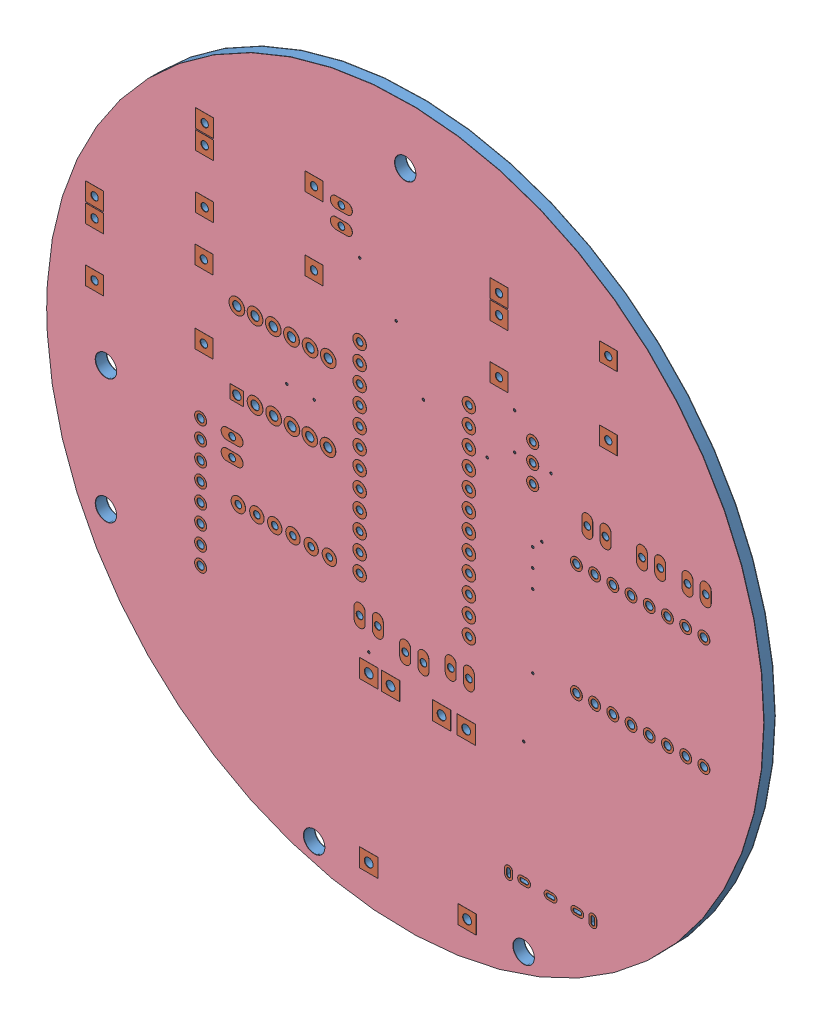
SolidWorks assembly RolyPoly PCB v1 SLDWRKS, configuration Default. Lengths in mm.
Overall size (100 100 1.64).
6 component instances, 5 part files, 0 mates.
Components (placement in the parent):
- RolyPoly PCB v1.step-1: RolyPoly PCB v1.step [Default] at origin size (100 100 1.64)
  - Board.step-1: Board.step [Default] at origin size (100 100 1.5)
  - 1-copper.step-1: 1-copper.step [Default] at (0 0 1.5) size (91.04 84.59 0.07)
  - 16-copper.step-1: 16-copper.step [Default] at (0 0 -0.035) size (97.81 97.81 0.07)
  - 1-soldermask.step-1: 1-soldermask.step [Default] at (0 0 1.5) size (100 100 0.05)
  - 16-soldermask.step-1: 16-soldermask.step [Default] at origin size (100 100 0.05)
